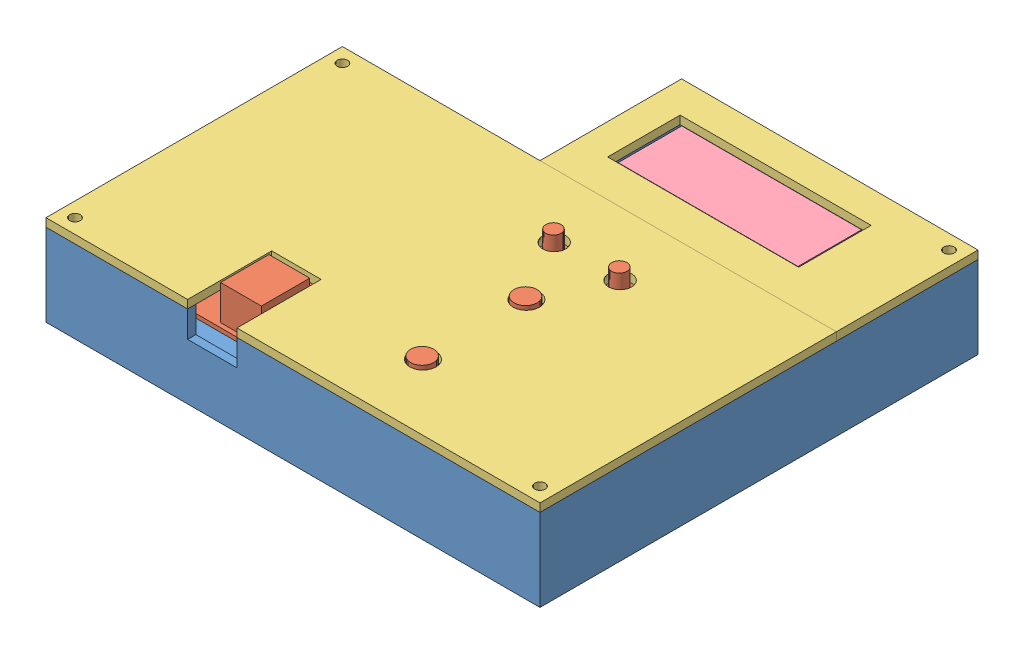
SolidWorks assembly UI_BOX_ASSEM, configuration Default. Lengths in mm.
Overall size (190.5 39.67 168.91).
4 component instances, 4 part files, 10 mates.
Components (placement in the parent):
- UI_Box-1: UI_Box [Default] at (-26.0603 74.0092 208.7045) size (190.5 31.75 168.91)
- UI_PCB-1: UI_PCB [Default] at (154.3704 94.9642 104.1264) x (-1 0 0) z (0 0 -1) size (169.86 33.2 95.25)
- UI_Box_Top-1: UI_Box_Top [Default] at (154.2542 105.7592 103.7009) x (-1 0 0) z (0 1 0) size (190.5 168.91 3.17)
- LCD-1: LCD [Default] at (59.5885 99.1552 84.0159) size (79.81 15.89 53.21)
Mates (geometry in assembly coordinates):
- Coincident1: coincident anti-aligned: plane of UI_Box-1 through (143.5436 94.9642 114.0895) normal (0 1 0); plane of UI_PCB-1 through (154.3704 94.9642 104.1264) normal (0 -1 0)
- Concentric2: concentric anti-aligned: cylinder of UI_Box-1 through (-5.6814 94.9642 114.0895) axis (0 -1 0) radius 5.08; cylinder of UI_PCB-1 through (-5.6814 82.0356 114.0895) axis (0 1 0) radius 2.9527
- Parallel2: parallel aligned: plane of UI_Box-1 through (-26.0603 105.7592 208.7045) normal (0 0 1); plane of UI_PCB-1 through (154.3704 96.5136 199.3764) normal (0 0 1)
- Coincident2: coincident anti-aligned: plane of UI_Box-1 through (-26.0603 105.7592 208.7045) normal (0 1 0); plane of UI_Box_Top-1 through (154.2542 105.7592 103.7009) normal (0 -1 0)
- Parallel3: parallel aligned: plane of UI_Box-1 through (-26.0603 105.7592 94.4045) normal (0 0 -1); plane of UI_Box_Top-1 through (154.2542 108.9342 94.4045) normal (0 0 -1)
- Coincident3: coincident aligned: plane of UI_Box-1 through (-26.0603 105.7592 94.4045) normal (0 0 -1); plane of UI_Box_Top-1 through (154.2542 108.9342 94.4045) normal (0 0 -1)
- Coincident4: coincident aligned: plane of UI_Box-1 through (-26.0603 105.7592 208.7045) normal (-1 0 0); plane of UI_Box_Top-1 through (-26.0603 108.9342 103.7009) normal (-1 0 0)
- Parallel4: parallel: plane of UI_Box-1 through (53.3147 77.1842 42.9695) normal (1 0 0); line of LCD-1 through (59.5885 100.5776 47.9733) axis (0 0 1)
- Concentric5: concentric aligned: cylinder of UI_Box-1 through (62.0777 86.4552 50.4625) axis (0 1 0) radius 1.3716; circle of LCD-1
- Coincident5: coincident anti-aligned: plane of UI_Box-1 through (62.0777 99.1552 50.4625) normal (0 1 0); plane of LCD-1 through (59.5885 99.1552 84.0159) normal (0 -1 0)
